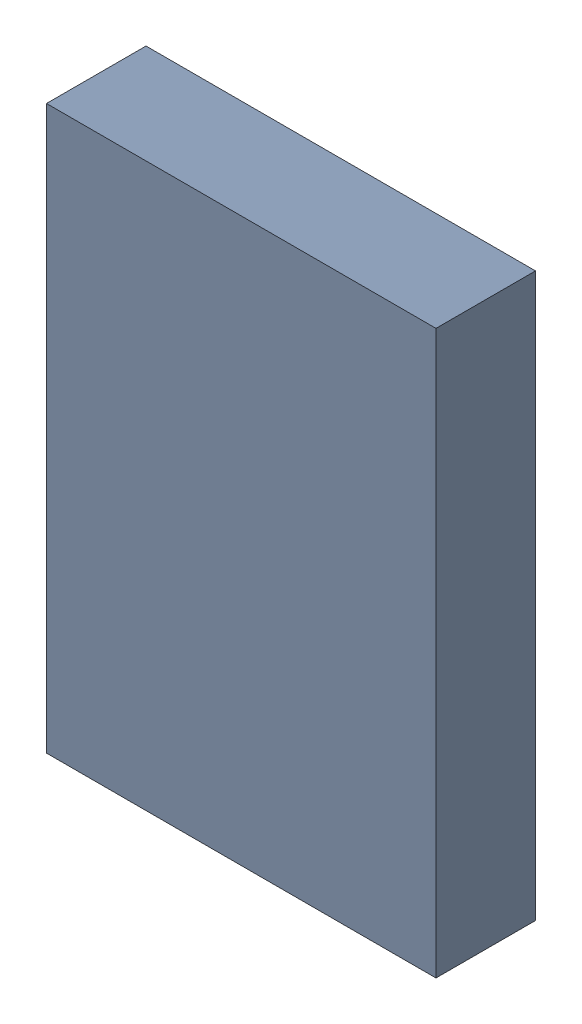
SolidWorks assembly U2Kanaloa_v2.0.0_Motor, configuration Default. Lengths in mm.
Overall size (4.5 6.5 1.15).
2 component instances, 1 part files, 0 mates.
Components (placement in the parent):
- 334789680-1: 334789680 [Default] at (38.862 111.76 0) size (4.5 6.5 1.15)
  - Extruded_17-1: Extruded_17 [Default] at origin size (4.5 6.5 1.15)
